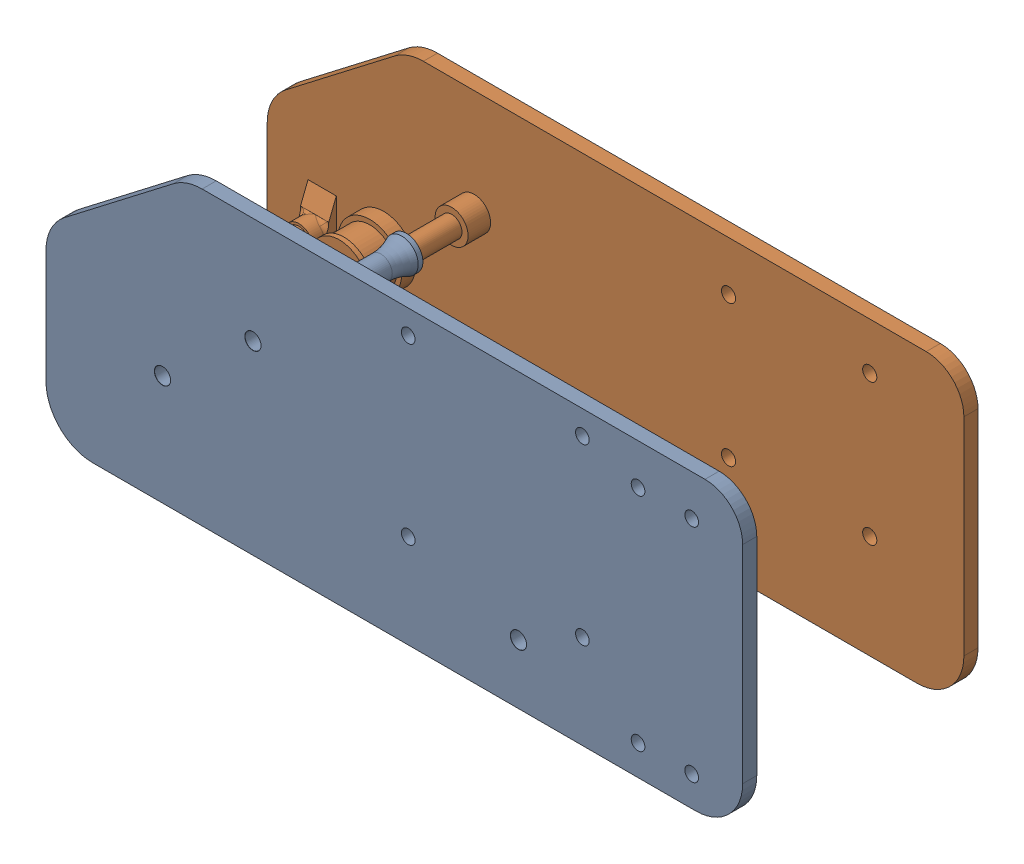
SolidWorks assembly Body, configuration Default. Lengths in mm.
Overall size (148 62 50).
2 component instances, 2 part files, 0 mates.
Components (placement in the parent):
- Plate_dx_print-1: Plate_dx_print [Default] at (53.8252 -17.6378 156.3946) size (148 62 32.62)
- Plate_sx_print-1: Plate_sx_print [Default] at (-6.7243 7.6417 112.3946) x (-1 0 0) z (0 0 -1) size (148 62 23.6)
